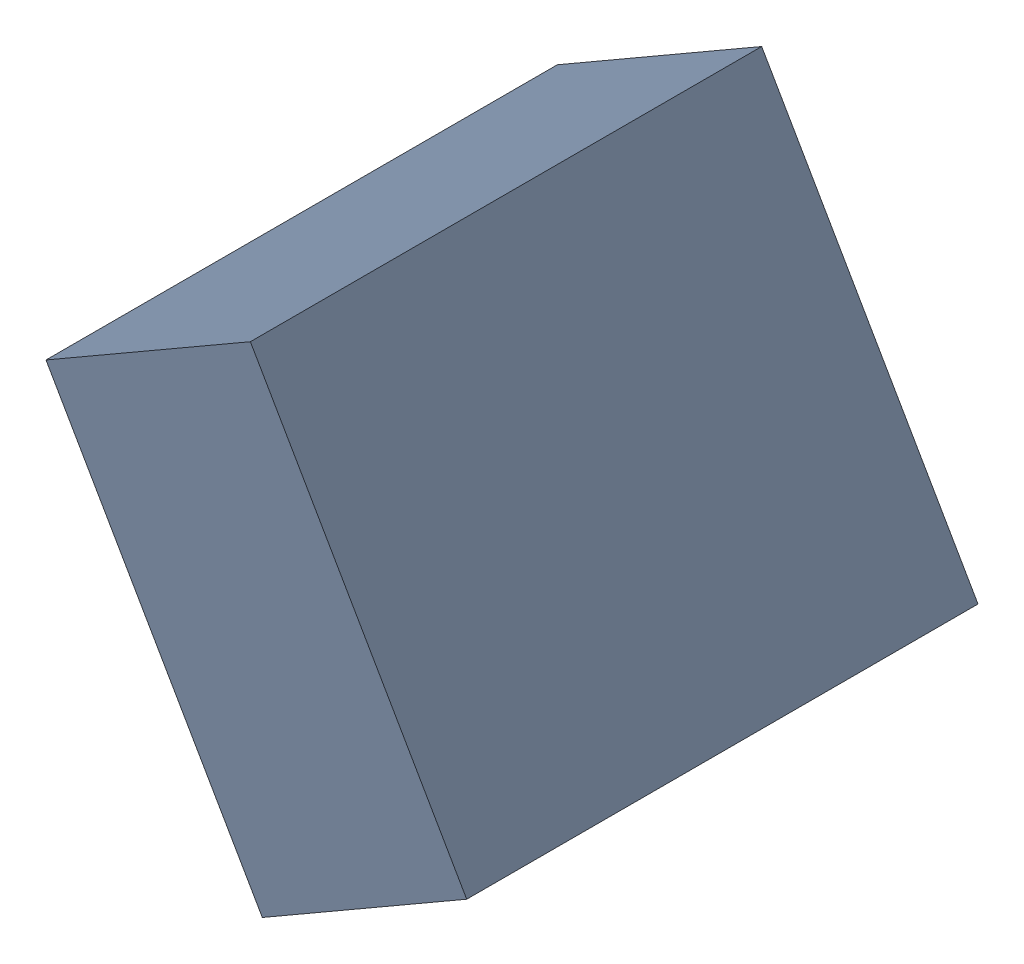
SolidWorks assembly C29_TDA2, configuration Standard. Lengths in mm.
Overall size (1.07 1.25 1.3).
2 component instances, 1 part files, 0 mates.
Components (placement in the parent):
- 885543192-1: 885543192 [Standard] at (48.7475 31.5621 0) size (1.07 1.25 1.3)
  - Extruded_27-1: Extruded_27 [Standard] at origin size (1.07 1.25 1.3)
